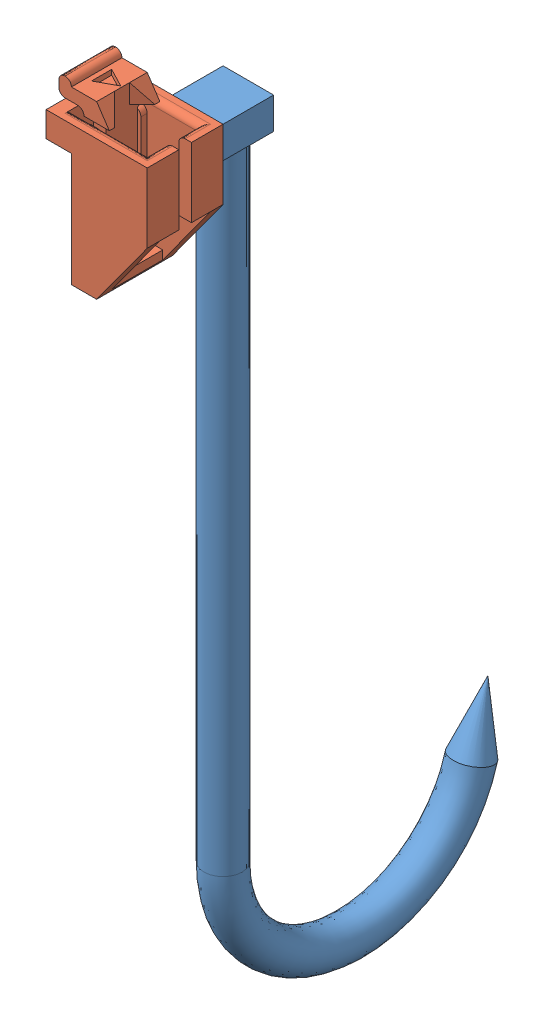
SolidWorks assembly Stylus_Candycane_100mm_WithHolder, configuration Default. Lengths in mm.
Overall size (16 132.1 58.22).
2 component instances, 2 part files, 6 mates.
Components (placement in the parent):
- CandyCaneTip_100mm-1: CandyCaneTip_100mm [Default] at (16.8104 6.2932 24.5465) x (0 0 -1) z (-1 0 0) size (46.22 128 8)
- SensorHolder_2.0-1: SensorHolder_2.0 [Default] at (11.0781 -15.7068 32.515) size (16 26.1 12)
Mates (geometry in assembly coordinates):
- Coincident1: coincident anti-aligned: plane of ? through (11.0781 6.2932 24.3072) normal (0 -1 0); plane of CandyCaneTip_100mm-1 through (8.8104 6.2932 28.3387) normal (0 1 0)
- Coincident2: coincident aligned: plane of ? through (4.8104 8.2932 32.3387) normal (0 0 1); plane of CandyCaneTip_100mm-1 through (12.8104 1.2932 32.3387) normal (0 0 1)
- Coincident3: coincident aligned: plane of ? through (4.8104 8.2932 20.3387) normal (-1 0 0); plane of CandyCaneTip_100mm-1 through (4.8104 1.2932 32.3387) normal (-1 0 0)
- Coincident4: coincident: plane of CandyCaneTip_100mm-1 through (12.8104 1.2932 28.5465) normal (0 0 1); plane of SensorHolder_2.0-1 through (4.8104 -13.7068 28.5465) normal (0 0 -1)
- Coincident5: coincident: plane of CandyCaneTip_100mm-1 through (20.8104 1.2932 28.5465) normal (1 0 0); plane of SensorHolder_2.0-1 through (20.8104 -13.7068 28.5465) normal (1 0 0)
- Coincident6: coincident aligned: plane of CandyCaneTip_100mm-1 through (16.8104 6.2932 24.5465) normal (0 1 0); plane of SensorHolder_2.0-1 through (11.0781 6.2932 32.515) normal (0 1 0)
